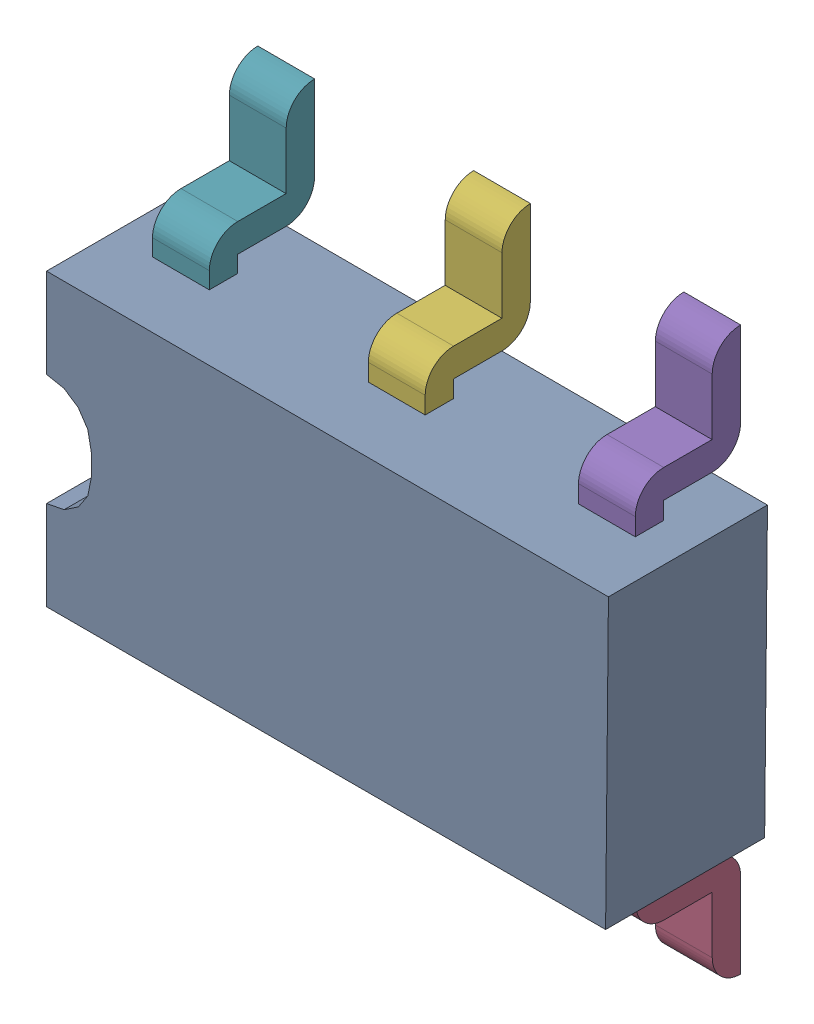
SolidWorks assembly U5, configuration Défaut. Lengths in mm.
Overall size (2.51 2.51 0.76).
8 component instances, 7 part files, 0 mates.
Components (placement in the parent):
- Open CASCADE STEP translator 6.8 1.31.1-1: Open CASCADE STEP translator 6.8 1.31.1 [Défaut] at origin size (2.51 2.51 0.76)
  - Body_1_15-1: Body_1_15 [Défaut] at origin size (2.51 1.3 0.71)
  - Pin_1_11-1: Pin_1_11 [Défaut] at (-2.1844 -0.254 0) x (0 1 0) z (0 0 1) size (0.63 0.25 0.47)
  - Pin_2_11-1: Pin_2_11 [Défaut] at (-1.2446 -1.1938 0) x (0 1 0) z (0 0 1) size (0.63 0.25 0.47)
  - Pin_3_7-1: Pin_3_7 [Défaut] at (-0.2794 -2.159 0) x (0 1 0) z (0 0 1) size (0.63 0.25 0.47)
  - Pin_4_5-1: Pin_4_5 [Défaut] at (-0.2267 2.1106 0) x (-0.002065 -0.999998 0) z (0 0 1) size (0.59 0.25 0.47)
  - Pin_5_4-1: Pin_5_4 [Défaut] at (-1.1684 1.1708 0) x (-0.002073 -0.999998 0) z (0 0 1) size (0.58 0.25 0.47)
  - Pin_6_4-1: Pin_6_4 [Défaut] at (-2.1356 0.2056 0) x (-0.002061 -0.999998 0) z (0 0 1) size (0.58 0.25 0.47)
